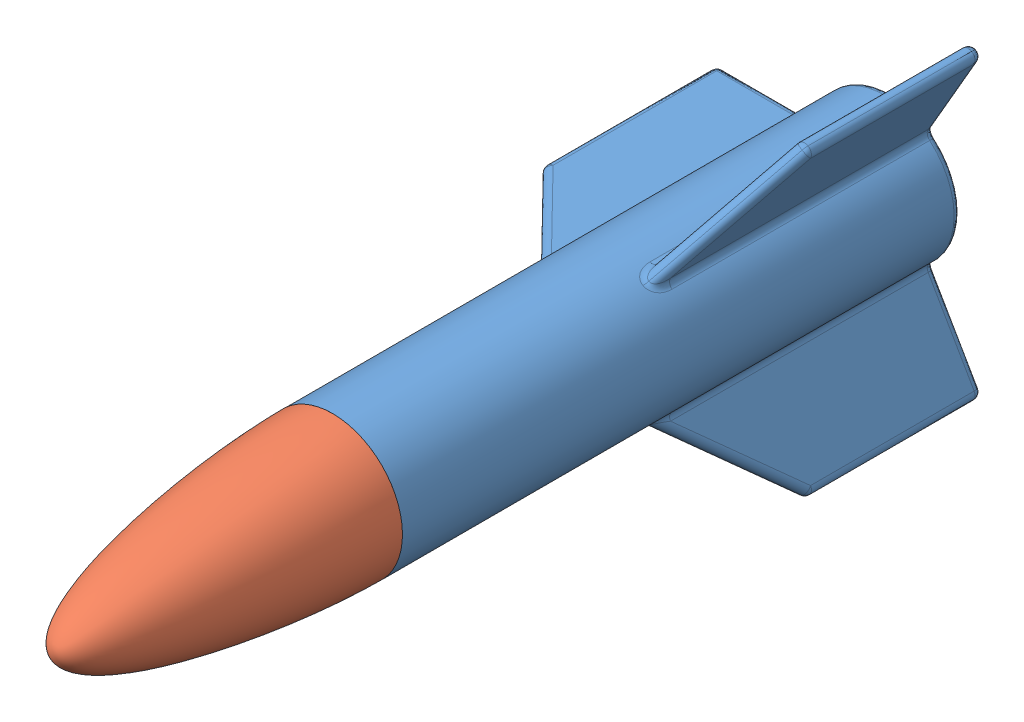
SolidWorks assembly MS-A-0013-Torpedo - 6fins, configuration Default. Lengths in mm.
Overall size (48.87 55.33 152.4).
2 component instances, 2 part files, 1 mates.
Components (placement in the parent):
- MS-P-0042-Torpedo Body-3: MS-P-0042-Torpedo Body [Default] at (40.6803 77.5366 59.8766) size (48.26 55.33 101.6)
- MS-P-0041-Nose Cone-1: MS-P-0041-Nose Cone [Default] at (40.6803 77.5366 161.4766) x (-0.888161 0.459533 0) z (0.459533 0.888161 0) size (25.4 50.8 25.4)
Mates (geometry in assembly coordinates):
- Coincident3: coincident anti-aligned: circle of MS-P-0042-Torpedo Body-3; circle of MS-P-0041-Nose Cone-1
